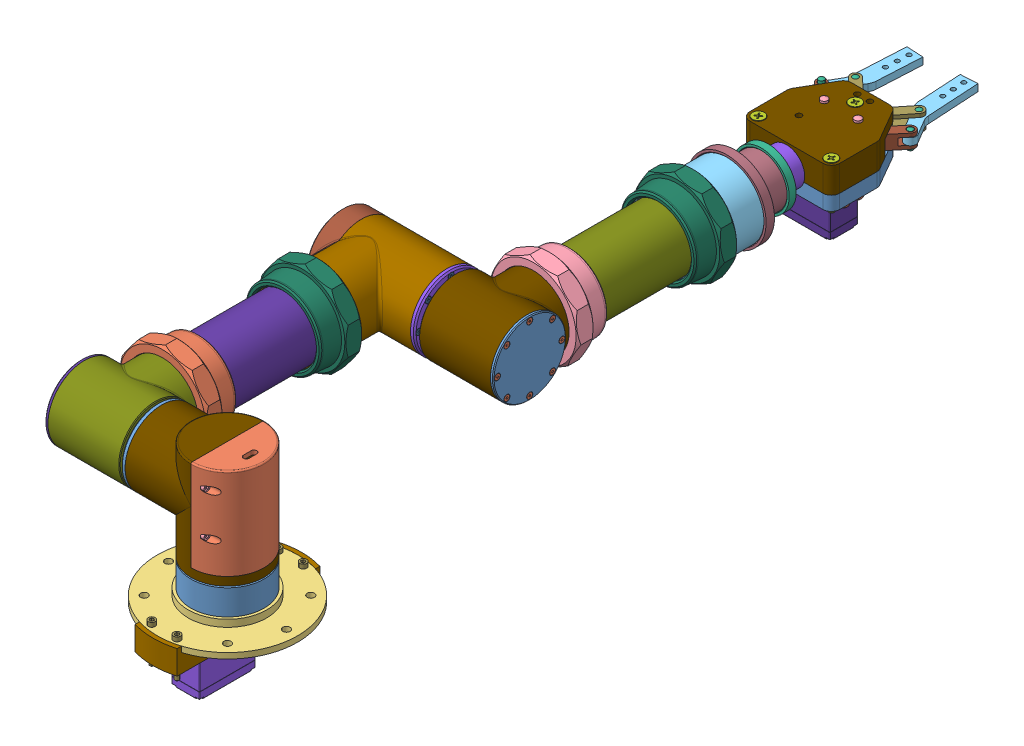
SolidWorks assembly СборкаМанипулятораИСхвата, configuration По умолчанию. Lengths in mm.
Overall size (176.26 169.71 563.94).
209 component instances, 76 part files, 12 mates.
Components (placement in the parent):
- link_0-1: link_0 [По умолчанию] at origin size (100 73 106)
  - shell_0-2: shell_0 [По умолчанию] x (-1 0 0) z (0 -1 0) size (52 52 23)
  - sleave_external_0-1: sleave_external_0 [00] at (0 12 0) x (0 -1 0) z (0.129917 0 0.991525) size (3 42 42)
  - flange_0-1: flange_0 [По умолчанию] at (0 -4 0) size (100 9 100)
  - screw_M3x10(DIN7991)-1: screw_M3x10(DIN7991) [По умолчанию] at (-11.75 -4 20.3516) x (0.992464 0 0.122536) z (0 -1 0) size (6.72 6.72 10)
  - screw_M3x10(DIN7991)-2: screw_M3x10(DIN7991) [По умолчанию] at (11.75 -4 20.3516) x (0.602352 0 -0.798231) z (0 -1 0) size (6.72 6.72 10)
  - screw_M3x10(DIN7991)-3: screw_M3x10(DIN7991) [По умолчанию] at (23.5 -4 0) x (-0.390112 0 -0.920767) z (0 -1 0) size (6.72 6.72 10)
  - screw_M3x10(DIN7991)-4: screw_M3x10(DIN7991) [По умолчанию] at (11.75 -4 -20.3516) x (-0.992464 0 -0.122536) z (0 -1 0) size (6.72 6.72 10)
  - screw_M3x10(DIN7991)-5: screw_M3x10(DIN7991) [По умолчанию] at (-11.75 -4 -20.3516) x (-0.602352 0 0.798231) z (0 -1 0) size (6.72 6.72 10)
  - screw_M3x10(DIN7991)-6: screw_M3x10(DIN7991) [По умолчанию] at (-23.5 -4 0) x (0.390112 0 0.920767) z (0 -1 0) size (6.72 6.72 10)
  - shaft_0-1: shaft_0 [00] at (0 -4 0) x (0 -1 0) z (-0.151353 0 -0.98848) size (31 32 32)
  - servo_flange-1: servo_flange [По умолчанию] at (0 -1.5 0) x (-0.591938 0 0.805983) z (0.805983 0 0.591938) size (20 4.5 20)
  - screw_M3x8(DIN912)-1: screw_M3x8(DIN912) [По умолчанию] at (5.6419 -6 4.1436) x (-0.618765 0 -0.785576) z (0 -1 0) size (4.6 4.6 10)
  - screw_M3x8(DIN912)-2: screw_M3x8(DIN912) [По умолчанию] at (-4.1436 -6 5.6419) x (0.785576 0 -0.618765) z (0 -1 0) size (4.6 4.6 10)
  - screw_M3x8(DIN912)-3: screw_M3x8(DIN912) [По умолчанию] at (-5.6419 -6 -4.1436) x (0.618765 0 0.785576) z (0 -1 0) size (4.6 4.6 10)
  - screw_M3x8(DIN912)-4: screw_M3x8(DIN912) [По умолчанию] at (4.1436 -6 -5.6419) x (-0.785576 0 0.618765) z (0 -1 0) size (4.6 4.6 10)
  - servo_MG995-1: servo_MG995 [По умолчанию] at (0 -46 10) x (0 0 -1) z (0 1 0) size (55.5 20 44.57)
  - servo_lock-1: servo_lock [По умолчанию] at (0 -17 0) size (30 17 106)
  - screw_M4x14(DIN912)-1: screw_M4x14(DIN912) [По умолчанию] at (-5 -23 -14) x (0.91175 0 0.410745) z (0 -1 0) size (7 7 18)
  - ГайкаM4(DIN936)-1: ГайкаM4(DIN936) [По умолчанию] at (-5 -9 -14) size (7 2.2 8.08)
  - screw_M4x14(DIN912)-2: screw_M4x14(DIN912) [По умолчанию] at (5 -23 -14) x (0.91175 0 0.410745) z (0 -1 0) size (7 7 18)
  - screw_M4x14(DIN912)-3: screw_M4x14(DIN912) [По умолчанию] at (-5 -23 34) x (0.91175 0 0.410745) z (0 -1 0) size (7 7 18)
  - screw_M4x14(DIN912)-4: screw_M4x14(DIN912) [По умолчанию] at (5 -23 34) x (0.91175 0 0.410745) z (0 -1 0) size (7 7 18)
  - ГайкаM4(DIN936)-2: ГайкаM4(DIN936) [По умолчанию] at (5 -9 -14) size (7 2.2 8.08)
  - ГайкаM4(DIN936)-3: ГайкаM4(DIN936) [По умолчанию] at (-5 -9 34) size (7 2.2 8.08)
  - ГайкаM4(DIN936)-4: ГайкаM4(DIN936) [По умолчанию] at (5 -9 34) size (7 2.2 8.08)
  - screw_M3x25(DIN912)-1: screw_M3x25(DIN912) [По умолчанию] at (-9 3 45) x (0.945557 0 -0.325458) z (0 1 0) size (5 5 28)
  - screw_M3x25(DIN912)-2: screw_M3x25(DIN912) [По умолчанию] at (9 3 45) x (0.945557 0 -0.325458) z (0 1 0) size (5 5 28)
  - screw_M3x25(DIN912)-3: screw_M3x25(DIN912) [По умолчанию] at (-9 3 -45) x (0.945557 0 -0.325458) z (0 1 0) size (5 5 28)
  - screw_M3x25(DIN912)-4: screw_M3x25(DIN912) [По умолчанию] at (9 3 -45) x (0.945557 0 -0.325458) z (0 1 0) size (5 5 28)
  - bearing_6905-2RS_0-1: bearing_6905-2RS_0 [00] at (0 21 0) x (0 -1 0) z (-0.716466 0 0.697622) size (9 42 42)
  - sleave_internal_0-1: sleave_internal_0 [00] at (0 12 0) x (0 -1 0) z (0.154614 0 0.987975) size (3 29 29)
  - bearing_6905-2RS_0-2: bearing_6905-2RS_0 [00] at (0 9 0) x (0 -1 0) z (-0.456957 0 0.889489) size (9 42 42)
  - circlip for shafts normal_din-1: circlip for shafts normal_din [Circlip DIN 471 - 25 x 1.2] x (0.876628 0 0.481168) z (0 1 0) size (28.33 31.3 1.2)
- link_2-1: link_2 [00] at (-56 68 0) x (0 0 -1) z (-1 0 0) size (248.92 79.84 95.06)
  - link_2_part_1-1: link_2_part_1 [00] at origin size (82.24 79.84 84.11)
    - case_2_part_1-1: case_2_part_1 [По умолчанию] at origin size (79.09 52.19 55.06)
    - case_cover_2_part_1-1: case_cover_2_part_1 [По умолчанию] at (0 0 46) size (52 52 2)
    - screw_M2x8(DIN7991)_2_part_1-1: screw_M2x8(DIN7991)_2_part_1 [Default] at (-23 0 46.8) x (0 0 -1) z (1 0 0) size (8 4 4)
    - screw_M2x8(DIN7991)_2_part_1-2: screw_M2x8(DIN7991)_2_part_1 [Default] at (-16.2635 16.2635 46.8) x (0 0 -1) z (1 0 0) size (8 4 4)
    - screw_M2x8(DIN7991)_2_part_1-3: screw_M2x8(DIN7991)_2_part_1 [Default] at (0 23 46.8) x (0 0 -1) z (1 0 0) size (8 4 4)
    - screw_M2x8(DIN7991)_2_part_1-4: screw_M2x8(DIN7991)_2_part_1 [Default] at (16.2635 16.2635 46.8) x (0 0 -1) z (1 0 0) size (8 4 4)
    - screw_M2x8(DIN7991)_2_part_1-5: screw_M2x8(DIN7991)_2_part_1 [Default] at (23 0 46.8) x (0 0 -1) z (1 0 0) size (8 4 4)
    - screw_M2x8(DIN7991)_2_part_1-6: screw_M2x8(DIN7991)_2_part_1 [Default] at (16.2635 -16.2635 46.8) x (0 0 -1) z (1 0 0) size (8 4 4)
    - screw_M2x8(DIN7991)_2_part_1-7: screw_M2x8(DIN7991)_2_part_1 [Default] at (0 -23 46.8) x (0 0 -1) z (1 0 0) size (8 4 4)
    - screw_M2x8(DIN7991)_2_part_1-8: screw_M2x8(DIN7991)_2_part_1 [Default] at (-16.2635 -16.2635 46.8) x (0 0 -1) z (1 0 0) size (8 4 4)
    - bolt_M3x8(DIN912)_2_part_1-1: bolt_M3x8(DIN912)_2_part_1 [По умолчанию] at (4.9497 -4.9497 2) size (4.6 4.6 10)
    - bolt_M3x8(DIN912)_2_part_1-3: bolt_M3x8(DIN912)_2_part_1 [По умолчанию] at (-4.9497 -4.9497 2) size (4.6 4.6 10)
    - bolt_M3x8(DIN912)_2_part_1-4: bolt_M3x8(DIN912)_2_part_1 [По умолчанию] at (-4.9497 4.9497 2) size (4.6 4.6 10)
    - bolt_M3x8(DIN912)_2_part_1-5: bolt_M3x8(DIN912)_2_part_1 [По умолчанию] at (4.9497 4.9497 2) size (4.6 4.6 10)
    - collet_nut_2_part_1-4: collet_nut_2_part_1 [По умолчанию] at (42.2 0 20.5) x (0 -0.949647 -0.313322) z (0 -0.313322 0.949647) size (61.55 26.55 68.27)
  - link_2_part_2-2: link_2_part_2 [00] at (186 0 -1.5) x (0 0 1) z (-0.003987 0.999992 0) size (83.78 107.15 73.54)
    - shaft_2-1: shaft_2 [00] x (1 0 0) z (0 0.906251 -0.422741) size (31 32 32)
    - bearing_6905-2RS-1: bearing_6905-2RS [00] at (-25 0 0) size (9 42 42)
    - sleave_internal_2-1: sleave_internal_2 [00] at (-16 0 0) size (3 29 29)
    - sleave_external_2-2: sleave_external_2 [00] at (-16 0 0) size (3 42 42)
    - bearing_6905-2RS-2: bearing_6905-2RS [00] at (-13 0 0) size (9 42 42)
    - servo_flange_2-1: servo_flange_2 [По умолчанию] at (-2.5 0 0) x (0 -0.341893 0.939739) z (0 0.939739 0.341893) size (20 4.5 20)
    - bearing_cover_2-1: bearing_cover_2 [00] at (-28 0 0) x (1 0 0) z (0 0.709921 0.704282) size (3.19 52 52)
    - case_2_part_2-3: case_2_part_2 [00] at (-25 0 0) x (1 0 0) z (0 0.003987 0.999992) size (72.93 93 52.14)
    - servo_MG995-2: servo_MG995 [По умолчанию] at (42 -9.9999 0.0399) x (0 0.999992 -0.003987) z (-1 0 0) size (55.5 20 44.57)
    - screw_M2x10(DIN7991)_2_part_2-2: screw_M2x10(DIN7991)_2_part_2 [Default] at (-26.8 22.9998 -0.0917) x (1 0 0) z (0 -0.003987 -0.999992) size (10 4 4)
    - case_cover_2_part_2-2: case_cover_2_part_2 [00] at (22 0 0) x (0 -0.999992 0.003987) z (0 0.003987 0.999992) size (63 17.67 52)
    - servo_lock_2-1: servo_lock_2 [00] at (8 0 0) x (0 -0.003987 -0.999992) z (1 0 0) size (50 59.91 32.5)
    - bolt_M3x8(DIN912)-1: bolt_M3x8(DIN912) [По умолчанию] at (17 14.0198 4.9441) x (0 -0.003987 -0.999992) z (1 0 0) size (4.6 4.6 10)
    - screw_M2x10(DIN7991)_2_part_2-13: screw_M2x10(DIN7991)_2_part_2 [Default] at (-26.8 16.3282 16.1985) x (1 0 0) z (0 -0.003987 -0.999992) size (10 4 4)
    - screw_M2x10(DIN7991)_2_part_2-14: screw_M2x10(DIN7991)_2_part_2 [Default] at (-26.8 0.0917 22.9998) x (1 0 0) z (0 -0.003987 -0.999992) size (10 4 4)
    - screw_M2x10(DIN7991)_2_part_2-15: screw_M2x10(DIN7991)_2_part_2 [Default] at (-26.8 -16.1985 16.3282) x (1 0 0) z (0 -0.003987 -0.999992) size (10 4 4)
    - screw_M2x10(DIN7991)_2_part_2-16: screw_M2x10(DIN7991)_2_part_2 [Default] at (-26.8 -22.9998 0.0917) x (1 0 0) z (0 -0.003987 -0.999992) size (10 4 4)
    - screw_M2x10(DIN7991)_2_part_2-17: screw_M2x10(DIN7991)_2_part_2 [Default] at (-26.8 -16.3282 -16.1985) x (1 0 0) z (0 -0.003987 -0.999992) size (10 4 4)
    - screw_M2x10(DIN7991)_2_part_2-18: screw_M2x10(DIN7991)_2_part_2 [Default] at (-26.8 -0.0917 -22.9998) x (1 0 0) z (0 -0.003987 -0.999992) size (10 4 4)
    - screw_M2x10(DIN7991)_2_part_2-19: screw_M2x10(DIN7991)_2_part_2 [Default] at (-26.8 16.1985 -16.3282) x (1 0 0) z (0 -0.003987 -0.999992) size (10 4 4)
    - bolt_M3x8(DIN912)-10: bolt_M3x8(DIN912) [По умолчанию] at (2 -2.3933 6.5782) x (0 -0.868012 -0.496543) z (1 0 0) size (4.6 4.6 10)
    - bolt_M3x8(DIN912)-11: bolt_M3x8(DIN912) [По умолчанию] at (2 6.5782 2.3933) x (0 -0.868012 -0.496543) z (1 0 0) size (4.6 4.6 10)
    - bolt_M3x8(DIN912)-12: bolt_M3x8(DIN912) [По умолчанию] at (2 2.3933 -6.5782) x (0 -0.868012 -0.496543) z (1 0 0) size (4.6 4.6 10)
    - bolt_M3x8(DIN912)-13: bolt_M3x8(DIN912) [По умолчанию] at (2 -6.5782 -2.3933) x (0 -0.868012 -0.496543) z (1 0 0) size (4.6 4.6 10)
    - bolt_M3x8(DIN912)-15: bolt_M3x8(DIN912) [По умолчанию] at (17 13.98 -5.0558) x (0 -0.003987 -0.999992) z (1 0 0) size (4.6 4.6 10)
    - bolt_M3x8(DIN912)-16: bolt_M3x8(DIN912) [По умолчанию] at (17 -33.9798 5.1355) x (0 -0.003987 -0.999992) z (1 0 0) size (4.6 4.6 10)
    - bolt_M3x8(DIN912)-17: bolt_M3x8(DIN912) [По умолчанию] at (17 -34.0197 -4.8644) x (0 -0.003987 -0.999992) z (1 0 0) size (4.6 4.6 10)
    - screw_M2x16(DIN7991)_2_part_2-6: screw_M2x16(DIN7991)_2_part_2 [Default] at (48.3 0.0917 22.9998) x (-1 0 0) z (0 -0.003987 -0.999992) size (16 4 4)
    - screw_M2x16(DIN7991)_2_part_2-7: screw_M2x16(DIN7991)_2_part_2 [Default] at (48.3 16.3282 16.1985) x (-1 0 0) z (0 -0.003987 -0.999992) size (16 4 4)
    - screw_M2x16(DIN7991)_2_part_2-8: screw_M2x16(DIN7991)_2_part_2 [Default] at (48.3 22.9998 -0.0917) x (-1 0 0) z (0 -0.003987 -0.999992) size (16 4 4)
    - screw_M2x16(DIN7991)_2_part_2-9: screw_M2x16(DIN7991)_2_part_2 [Default] at (48.3 16.1985 -16.3282) x (-1 0 0) z (0 -0.003987 -0.999992) size (16 4 4)
    - screw_M2x16(DIN7991)_2_part_2-10: screw_M2x16(DIN7991)_2_part_2 [Default] at (48.3 -0.0917 -22.9998) x (-1 0 0) z (0 -0.003987 -0.999992) size (16 4 4)
    - collet_nut_2_part_2-1: collet_nut_2_part_2 [По умолчанию] at (22 -56.1996 0.2241) x (-1 0 0) z (0 0.003987 0.999992) size (61.55 26.55 68.27)
    - circlip for shafts normal_din-1: circlip for shafts normal_din [Circlip DIN 471 - 25 x 1.2] at (-4 0 0) x (0 0.144431 0.989515) z (-1 0 0) size (28.33 31.3 1.2)
    - A_DB9-1: A_DB9 [По умолчанию] at (5.9719 -16.7195 3.89) x (1 0 0) z (0 0.003987 0.999992) size (30.9 12.5 15.5)
  - pipe_2-1: pipe_2 [По умолчанию] at (146 0 20.5) x (-1 0 0) z (0 -0.924225 -0.381849) size (120 45 45)
- link_3-1: link_3 [00] at (-18.5 68 -186) x (0 0 -1) z (1 0 0) size (230.5 111.41 111.41)
  - link_3_part_1-1: link_3_part_1 [00] at origin size (82.24 72.44 77.89)
    - case_3_part_1-2: case_3_part_1 [По умолчанию] at origin size (79.09 52.19 55.06)
    - case_cover_3_part_1-1: case_cover_3_part_1 [По умолчанию] at (0 0 46) size (52 52 2)
    - screw_M2x8(DIN7991)_3_part_1-1: screw_M2x8(DIN7991)_3_part_1 [Default] at (-23 0 46.8) x (0 0 -1) z (1 0 0) size (8 4 4)
    - screw_M2x8(DIN7991)_3_part_1-2: screw_M2x8(DIN7991)_3_part_1 [Default] at (-16.2635 16.2635 46.8) x (0 0 -1) z (1 0 0) size (8 4 4)
    - screw_M2x8(DIN7991)_3_part_1-3: screw_M2x8(DIN7991)_3_part_1 [Default] at (0 23 46.8) x (0 0 -1) z (1 0 0) size (8 4 4)
    - screw_M2x8(DIN7991)_3_part_1-4: screw_M2x8(DIN7991)_3_part_1 [Default] at (16.2635 16.2635 46.8) x (0 0 -1) z (1 0 0) size (8 4 4)
    - screw_M2x8(DIN7991)_3_part_1-5: screw_M2x8(DIN7991)_3_part_1 [Default] at (23 0 46.8) x (0 0 -1) z (1 0 0) size (8 4 4)
    - screw_M2x8(DIN7991)_3_part_1-6: screw_M2x8(DIN7991)_3_part_1 [Default] at (16.2635 -16.2635 46.8) x (0 0 -1) z (1 0 0) size (8 4 4)
    - screw_M2x8(DIN7991)_3_part_1-7: screw_M2x8(DIN7991)_3_part_1 [Default] at (0 -23 46.8) x (0 0 -1) z (1 0 0) size (8 4 4)
    - screw_M2x8(DIN7991)_3_part_1-8: screw_M2x8(DIN7991)_3_part_1 [Default] at (-16.2635 -16.2635 46.8) x (0 0 -1) z (1 0 0) size (8 4 4)
    - bolt_M3x8(DIN912)_3_part_1-1: bolt_M3x8(DIN912)_3_part_1 [По умолчанию] at (4.9497 -4.9497 2) size (4.6 4.6 10)
    - bolt_M3x8(DIN912)_3_part_1-2: bolt_M3x8(DIN912)_3_part_1 [По умолчанию] at (-4.9497 -4.9497 2) size (4.6 4.6 10)
    - bolt_M3x8(DIN912)_3_part_1-3: bolt_M3x8(DIN912)_3_part_1 [По умолчанию] at (-4.9497 4.9497 2) size (4.6 4.6 10)
    - bolt_M3x8(DIN912)_3_part_1-4: bolt_M3x8(DIN912)_3_part_1 [По умолчанию] at (4.9497 4.9497 2) size (4.6 4.6 10)
    - A_DB9-2: A_DB9 [По умолчанию] at (16.7349 -4.8234 11.4719) x (0 0 1) z (0 -1 0) size (30.9 12.5 15.5)
    - collet_nut_3_part_1-2: collet_nut_3_part_1 [По умолчанию] at (42.2 0 20.5) x (0 -0.984916 -0.173035) z (0 -0.173035 0.984916) size (61.55 26.55 68.27)
  - link_3_part_2-1: link_3_part_2 [По умолчанию] at (135 0 20.5) x (0 -0.775896 -0.63086) z (1 0 0) size (79.2 79.2 85.94)
    - case_3_part_2-2: case_3_part_2 [По умолчанию] at origin size (52.23 52.12 48.29)
    - case_cover_3_part_2-1: case_cover_3_part_2 [По умолчанию] at (0 0 59.5) x (-0.707107 -0.707107 0) z (0 0 1) size (40 40 5)
    - servo_MG90S-1: servo_MG90S [Default] at (-5.25 0 12) x (1 0 0) z (0 -1 0) size (32.2 32.5 12.4)
    - servo_flange_3-2: servo_flange_3 [По умолчанию] at (0 0 44.5) x (0.820742 -0.5713 0) z (0 0 -1) size (17 17 8)
    - bearing_6803-1: bearing_6803 [По умолчанию] at (0 0 54.5) x (0.864131 -0.503266 0) z (0 0 1) size (26 26 5)
    - bearing_6803-2: bearing_6803 [По умолчанию] at (0 0 53) x (-0.923728 -0.383049 0) z (0 0 -1) size (26 26 5)
    - shaft_3_part_2-1: shaft_3_part_2 [По умолчанию] at (0 0 44.5) x (-0.820742 0.5713 0) z (0.5713 0.820742 0) size (20 25 20)
    - ext_sleeve_3_part_2-1: ext_sleeve_3_part_2 [По умолчанию] at (0 0 54.5) x (-0.923728 -0.383049 0) z (0 0 -1) size (26 26 1.5)
    - int_sleeve_3_part_2-1: int_sleeve_3_part_2 [По умолчанию] at (0 0 54.5) x (-0.923728 -0.383049 0) z (0 0 -1) size (19 19 1.5)
    - nozzle_3_part_2-1: nozzle_3_part_2 [По умолчанию] at (0 0 35) x (0.707107 0.707107 0) z (0.707107 -0.707107 0) size (56 26.5 56)
    - screw_M2_3_part_2-1: screw_M2_3_part_2 [По умолчанию] at (-15.5563 -15.5563 38.6206) x (0 0 -1) z (-0.898959 0.438032 0) size (8 3.8 3.77)
    - screw_M2_3_part_2-2: screw_M2_3_part_2 [По умолчанию] at (-15.5563 15.5563 38.6206) x (0 0 -1) z (0.438032 0.898959 0) size (8 3.8 3.77)
    - screw_M2_3_part_2-3: screw_M2_3_part_2 [По умолчанию] at (15.5563 15.5563 38.6206) x (0 0 -1) z (0.898959 -0.438032 0) size (8 3.8 3.77)
    - screw_M2_3_part_2-4: screw_M2_3_part_2 [По умолчанию] at (15.5563 -15.5563 38.6206) x (0 0 -1) z (-0.438032 -0.898959 0) size (8 3.8 3.77)
    - screw_M2_3_part_2-5: screw_M2_3_part_2 [По умолчанию] at (10.9602 10.9602 62.1206) x (0 0 -1) z (0.997978 0.063567 0) size (8 3.8 3.77)
    - screw_M2_3_part_2-6: screw_M2_3_part_2 [По умолчанию] at (10.9602 -10.9602 62.1206) x (0 0 -1) z (0.063567 -0.997978 0) size (8 3.8 3.77)
    - screw_M2_3_part_2-7: screw_M2_3_part_2 [По умолчанию] at (-10.9602 -10.9602 62.1206) x (0 0 -1) z (-0.997978 -0.063567 0) size (8 3.8 3.77)
    - screw_M2_3_part_2-8: screw_M2_3_part_2 [По умолчанию] at (-10.9602 10.9602 62.1206) x (0 0 -1) z (-0.063567 0.997978 0) size (8 3.8 3.77)
    - collet_nut_3_part_2-2: collet_nut_3_part_2 [По умолчанию] at (0 0 -2.4) x (0.178047 0.984022 0) z (-0.984022 0.178047 0) size (61.55 26.55 68.27)
  - pipe_3-1: pipe_3 [По умолчанию] at (26 0 20.5) x (1 0 0) z (0 -0.068443 0.997655) size (120 45 45)
- Сборка схват-1: Сборка схват [По умолчанию] at (2.0001 25 -417.5) x (-1 0 0) z (0 1 0) size (84.23 127.44 59.75)
  - MG995-1: MG995 [По умолчанию] at origin size (55.5 20 44.57)
  - Корпус 2-1: Корпус 2 [По умолчанию] at (-31.9999 21 57.5) x (1 0 0) z (0 0 -1) size (64 60 18.5)
  - 1-1: 1 [По умолчанию] at (32 21 29) x (-1 0 0) z (0 0 1) size (64 60 10)
  - DIN912-M4x12-1: DIN912-M4x12 [По умолчанию] at (-24 -5 23) x (0 0 1) z (-0.460546 -0.887636 0) size (16.28 7 7)
  - DIN912-M4x12-2: DIN912-M4x12 [По умолчанию] at (24 5 23) x (0 0 1) z (-0.748354 -0.663299 0) size (16.28 7 7)
  - DIN912-M4x12-3: DIN912-M4x12 [По умолчанию] at (-24 5 23) x (0 0 1) z (-0.997931 0.0643 0) size (16.28 7 7)
  - DIN912-M4x12-4: DIN912-M4x12 [По умолчанию] at (24 -5 23) x (0 0 1) z (0.475534 0.879697 0) size (16.28 7 7)
  - DIN934-M4-2: DIN934-M4 [По умолчанию] at (-24 5 34.5) size (7.43 8.21 3.68)
  - DIN934-M4-3: DIN934-M4 [По умолчанию] at (24 5 34.5) size (7.43 8.21 3.68)
  - DIN934-M4-4: DIN934-M4 [По умолчанию] at (24 -5 34.5) size (7.43 8.21 3.68)
  - DIN934-M4-5: DIN934-M4 [По умолчанию] at (-24 -5 34.5) size (7.43 8.21 3.68)
  - DIN7 D5-L30-1: DIN7 D5-L30 [По умолчанию] at (12.0501 -18 59) x (0 0 -1) z (-0.738585 -0.67416 0) size (31.5 5 5)
  - DIN7 D5-L30-2: DIN7 D5-L30 [По умолчанию] at (-12.05 -18 29) x (0 0 1) z (-0.114483 -0.993425 0) size (31.5 5 5)
  - 6_GRIPPER_ARM-1: 6_GRIPPER_ARM [По умолчанию] at (19.5271 -90.1357 48) x (0.998564 -0.053577 0) z (0.053577 0.998564 0) size (19.3 5 59)
  - 6_GRIPPER_ARM-2: 6_GRIPPER_ARM [По умолчанию] at (-16.594 -92.6626 43) x (-0.998298 -0.058319 0) z (-0.058319 0.998298 0) size (19.3 5 59)
  - DIN7 D4-L12-1: DIN7 D4-L12 [По умолчанию] at (31.7605 -35.713 40.5) x (0 0 1) z (-0.956281 -0.292448 0) size (13.2 4 4)
  - DIN7 D4-L12-2: DIN7 D4-L12 [По умолчанию] at (-29.0857 -38.2986 50.5) x (0 0 -1) z (0.459318 0.888272 0) size (13.2 4 4)
  - DIN7046-1_M4x30-1: DIN7046-1_M4x30 [По умолчанию] at (26.0001 15 57.85) x (0 0 -1) z (0.831237 0.555919 0) size (33.09 8.4 8.4)
  - DIN7046-1_M4x30-2: DIN7046-1_M4x30 [По умолчанию] at (0 -28 57.85) x (0 0 -1) z (0.888568 -0.458744 0) size (33.09 8.4 8.4)
  - DIN7046-1_M4x30-3: DIN7046-1_M4x30 [По умолчанию] at (-26 15 57.85) x (0 0 -1) z (0.988915 -0.148483 0) size (33.09 8.4 8.4)
  - DIN934-M4-6: DIN934-M4 [По умолчанию] at (-26 15 29) size (7.43 8.21 3.68)
  - DIN934-M4-7: DIN934-M4 [По умолчанию] at (26 15 32.2) x (0.467399 -0.884046 0) z (0 0 -1) size (7.43 8.21 3.68)
  - DIN934-M4-8: DIN934-M4 [По умолчанию] at (0 -28 29) size (7.43 8.21 3.68)
  - ФланецСхват-1: ФланецСхват [По умолчанию] at (0.0001 34 43) x (0 -1 0) z (1 0 0) size (13 26 26)
  - втулка-2: втулка [По умолчанию] at (-12.05 -18 39) size (10 10 1.5)
  - втулка-3: втулка [По умолчанию] at (12.0501 -18 39) x (0.833208 0.552959 0) z (0 0 1) size (10 10 1.5)
  - втулка-4: втулка [По умолчанию] at (12.0501 -18 50.5) size (10 10 1.5)
  - втулка-6: втулка [По умолчанию] at (-11.3 -18 50.5) x (0.832508 0.554013 0) z (0 0 1) size (10 10 1.5)
  - ВалШестерня-3: ВалШестерня [Вал-шестерня] at (10 0 44.5) x (0 0 1) z (-0.995943 -0.08999 0) size (10 13.61 13.61)
  - КолесоКривошип-1: КолесоКривошип [Колесо-кривошип] at (12.0501 -18 44.5) x (0 0 1) z (0.668414 0.74379 0) size (10 42.92 25.84)
  - КолесоКривошип-2: КолесоКривошип [Колесо-кривошип] at (-12.05 -18 44.5) x (0 0 1) z (0.765986 -0.642858 0) size (10 42.92 25.84)
  - Кривошип-1: Кривошип [По умолчанию] at (-22.8002 -51.3883 39) x (0 0 1) z (-0.782673 0.622433 0) size (11.5 32 7)
  - DIN7 D4-L12-3: DIN7 D4-L12 [По умолчанию] at (-4.5 -34 38.5) x (0 0 1) z (-0.987062 -0.160337 0) size (13.2 4 4)
  - DIN7 D4-L12-4: DIN7 D4-L12 [По умолчанию] at (22.8082 -51.0239 38.5) x (0 0 1) z (0.96775 -0.251914 0) size (13.2 4 4)
  - DIN7 D4-L12-5: DIN7 D4-L12 [По умолчанию] at (4.5001 -34 50.5) x (0 0 -1) z (0.977007 -0.213205 0) size (13.2 4 4)
  - DIN7 D4-L12-6: DIN7 D4-L12 [По умолчанию] at (-20.0608 -53.5668 50.5) x (0 0 -1) z (0.991151 0.13274 0) size (13.2 4 4)
  - Кривошип-2: Кривошип [По умолчанию] at (20.4248 -53.587 39) x (0 0 1) z (-0.680955 -0.732326 0) size (11.5 32 7)
  - gayka_m2-1: gayka_m2 [По умолчанию] at (0 13.4 37) x (0.888267 0 -0.459328) z (0 1 0) size (4.25 4.76 2.06)
  - gayka_m2-2: gayka_m2 [По умолчанию] at (0.0001 13.4 49) x (0.888267 0 -0.459328) z (0 1 0) size (4.25 4.76 2.06)
  - gayka_m2-3: gayka_m2 [По умолчанию] at (-5.9999 13.4 43) x (0.888267 0 -0.459328) z (0 1 0) size (4.25 4.76 2.06)
  - gayka_m2-5: gayka_m2 [По умолчанию] at (6.0001 13.4 43) x (0.888267 0 -0.459328) z (0 1 0) size (4.25 4.76 2.06)
  - DIN912-M2x12-1: DIN912-M2x12 [По умолчанию] at (6.0001 26 43) x (0 -1 0) z (0.6502 0 0.759763) size (14.19 3.8 3.8)
  - DIN912-M2x12-2: DIN912-M2x12 [По умолчанию] at (0.0001 26 37) x (0 -1 0) z (0.733895 0 0.679263) size (14.19 3.8 3.8)
  - DIN912-M2x12-3: DIN912-M2x12 [По умолчанию] at (-5.9999 26 43) x (0 -1 0) z (0.223689 0 0.97466) size (14.19 3.8 3.8)
  - DIN912-M2x12-4: DIN912-M2x12 [По умолчанию] at (0.0001 26 49) x (0 -1 0) z (0.998157 0 0.060686) size (14.19 3.8 3.8)
- link_1-1: link_1 [00] at (75.0032 62.3733 78.1793) x (-0.958621 0.020437 -0.283952) z (0 -0.99742 -0.071787) size (90.29 75.39 79.42)
  - shaft_1-1: shaft_1 [00] at (115.3034 47.5227 0) x (-0.958621 0.284686 0) z (-0.241828 -0.814306 -0.52766) size (31 32 32)
  - servo_flange-1: servo_flange [По умолчанию] at (117.7 46.8109 0) x (-0.277218 -0.933474 0.227544) z (-0.064779 -0.218128 -0.973768) size (20 4.5 20)
  - bearing_6905-2RS-1: bearing_6905-2RS [00] at (139.2689 40.4055 0) x (-0.958621 0.284686 0) z (0 0 1) size (9 42 42)
  - bearing_6905-2RS-2: bearing_6905-2RS [00] at (127.7655 43.8217 0) x (-0.958621 0.284686 0) z (0 0 1) size (9 42 42)
  - sleave_external_1-1: sleave_external_1 [00] at (130.6414 42.9677 0) x (-0.958621 0.284686 0) z (0 0 1) size (3 42 42)
  - sleave_internal_1-1: sleave_internal_1 [00] at (130.6414 42.9677 0) x (-0.958621 0.284686 0) z (0 0 1) size (3 29 29)
  - case_1-1: case_1 [По умолчанию] at (93.3146 50.7578 43.8865) x (0.283952 0.956148 0.071787) z (-0.958621 0.284686 0) size (52 71 73)
  - servo_MG995-1: servo_MG995 [По умолчанию] at (74.3577 58.9337 9.9742) x (0.020437 0.068816 -0.99742) z (0.958621 -0.284686 0) size (55.5 20 44.57)
  - bearing_cover_1-1: bearing_cover_1 [00] at (142.1448 39.5515 0) x (-0.958621 0.284686 0) z (-0.020437 -0.068816 0.99742) size (3.19 52 52)
  - case_cover_1-2: case_cover_1 [По умолчанию] at (93.4372 51.1707 37.902) x (0.283952 0.956148 0.071787) z (-0.958621 0.284686 0) size (52 65 27.19)
  - slotted countersunk flat head screw_iso-39: slotted countersunk flat head screw_iso [ISO 2009 - M2 x 8 - 8N] at (135.6139 17.5601 -1.6511) x (-0.958621 0.284686 0) z (0.021773 0.073316 0.997071) size (8 3.8 3.77)
  - slotted countersunk flat head screw_iso-40: slotted countersunk flat head screw_iso [ISO 2009 - M2 x 8 - 8N] at (137.1944 22.882 15.054) x (-0.958621 0.284686 0) z (0.21611 0.727704 0.650956) size (8 3.8 3.77)
  - slotted countersunk flat head screw_iso-41: slotted countersunk flat head screw_iso [ISO 2009 - M2 x 8 - 8N] at (141.6748 37.9687 22.9407) x (-0.958621 0.284686 0) z (0.283852 0.955813 -0.076481) size (8 3.8 3.77)
  - slotted countersunk flat head screw_iso-42: slotted countersunk flat head screw_iso [ISO 2009 - M2 x 8 - 8N] at (146.4305 53.9825 17.389) x (-0.958621 0.284686 0) z (0.185318 0.62402 -0.759116) size (8 3.8 3.77)
  - slotted countersunk flat head screw_iso-43: slotted countersunk flat head screw_iso [ISO 2009 - M2 x 8 - 8N] at (148.6757 61.5428 1.6511) x (-0.958621 0.284686 0) z (-0.021773 -0.073316 -0.997071) size (8 3.8 3.77)
  - slotted countersunk flat head screw_iso-44: slotted countersunk flat head screw_iso [ISO 2009 - M2 x 8 - 8N] at (147.0952 56.2209 -15.054) x (-0.958621 0.284686 0) z (-0.21611 -0.727704 -0.650956) size (8 3.8 3.77)
  - slotted countersunk flat head screw_iso-45: slotted countersunk flat head screw_iso [ISO 2009 - M2 x 8 - 8N] at (142.6149 41.1342 -22.9407) x (-0.958621 0.284686 0) z (-0.283852 -0.955813 0.076481) size (8 3.8 3.77)
  - slotted countersunk flat head screw_iso-46: slotted countersunk flat head screw_iso [ISO 2009 - M2 x 8 - 8N] at (137.8591 25.1204 -17.389) x (-0.958621 0.284686 0) z (-0.185318 -0.62402 0.759116) size (8 3.8 3.77)
  - socket head cap screw_iso-25: socket head cap screw_iso [ISO 4762 M2.5 x 10 - 10N] at (79.8207 35.1776 -15.615) x (0.958621 -0.284686 0) z (0.249729 0.84091 -0.48011) size (12.5 4.5 4.5)
  - socket head cap screw_iso-29: socket head cap screw_iso [ISO 4762 M2.5 x 10 - 10N] at (79.2076 33.1131 14.3076) x (0.958621 -0.284686 0) z (0.249729 0.84091 -0.48011) size (12.5 4.5 4.5)
  - socket head cap screw_iso-27: socket head cap screw_iso [ISO 4762 M2.5 x 10 - 10N] at (92.8825 79.1604 -12.3128) x (0.958621 -0.284686 0) z (0.249729 0.84091 -0.48011) size (12.5 4.5 4.5)
  - socket head cap screw_iso-28: socket head cap screw_iso [ISO 4762 M2.5 x 10 - 10N] at (92.2694 77.0959 17.6098) x (0.958621 -0.284686 0) z (0.249729 0.84091 -0.48011) size (12.5 4.5 4.5)
  - socket head cap screw_iso-20: socket head cap screw_iso [ISO 4762 M3 x 8 - 8N] at (96.4353 48.972 -14.3228) x (0.958621 -0.284686 0) z (-0.07713 -0.259718 0.962599) size (11 5.5 5.5)
  - socket head cap screw_iso-24: socket head cap screw_iso [ISO 4762 M3 x 8 - 8N] at (95.4543 45.6689 33.5533) x (0.958621 -0.284686 0) z (-0.07713 -0.259718 0.962599) size (11 5.5 5.5)
  - socket head cap screw_iso-22: socket head cap screw_iso [ISO 4762 M3 x 8 - 8N] at (99.2748 58.5335 -13.6049) x (0.958621 -0.284686 0) z (-0.07713 -0.259718 0.962599) size (11 5.5 5.5)
  - socket head cap screw_iso-23: socket head cap screw_iso [ISO 4762 M3 x 8 - 8N] at (98.2939 55.2303 34.2712) x (0.958621 -0.284686 0) z (-0.07713 -0.259718 0.962599) size (11 5.5 5.5)
  - socket head cap screw_iso-4: socket head cap screw_iso [ISO 4762 M3 x 8 - 8N] at (112.881 49.9036 6.8164) x (0.958621 -0.284686 0) z (-0.083742 -0.281985 -0.955757) size (11 5.5 5.5)
  - socket head cap screw_iso-5: socket head cap screw_iso [ISO 4762 M3 x 8 - 8N] at (114.3681 54.911 -1.5928) x (0.958621 -0.284686 0) z (-0.272091 -0.916209 0.294157) size (11 5.5 5.5)
  - socket head cap screw_iso-6: socket head cap screw_iso [ISO 4762 M3 x 8 - 8N] at (111.9741 46.8498 -6.8164) x (0.958621 -0.284686 0) z (0.083742 0.281985 0.955757) size (11 5.5 5.5)
  - socket head cap screw_iso-7: socket head cap screw_iso [ISO 4762 M3 x 8 - 8N] at (110.487 41.8424 1.5928) x (0.958621 -0.284686 0) z (0.272091 0.916209 -0.294157) size (11 5.5 5.5)
  - slotted countersunk flat head screw_iso-47: slotted countersunk flat head screw_iso [ISO 2009 - M3 x 12 - 12N] at (91.4495 44.4777 37.3995) x (-0.020437 -0.068816 0.99742) z (0.9994 0.0265 0.022306) size (12 5.5 5.44)
  - slotted countersunk flat head screw_iso-48: slotted countersunk flat head screw_iso [ISO 2009 - M3 x 12 - 12N] at (86.7268 53.1635 37.902) x (-0.020437 -0.068816 0.99742) z (0.027967 -0.997277 -0.068233) size (12 5.5 5.44)
  - slotted countersunk flat head screw_iso-49: slotted countersunk flat head screw_iso [ISO 2009 - M3 x 12 - 12N] at (95.4248 57.8638 38.4045) x (-0.020437 -0.068816 0.99742) z (-0.9994 -0.0265 -0.022306) size (12 5.5 5.44)
  - slotted countersunk flat head screw_iso-50: slotted countersunk flat head screw_iso [ISO 2009 - M3 x 12 - 12N] at (100.1475 49.1779 37.902) x (-0.020437 -0.068816 0.99742) z (-0.027967 0.997277 0.068233) size (12 5.5 5.44)
  - circlip for shafts normal_din-1: circlip for shafts normal_din [Circlip DIN 471 - 25 x 1.2] at (119.1379 46.3839 0) x (0 0 -1) z (0.958621 -0.284686 0) size (28.33 31.3 1.2)
Mates (geometry in assembly coordinates):
- Концентричный4: concentric anti-aligned: cylinder of link_2-1/link_2_part_2-2/case_2_part_2-3 through (-29.5 68 -186) axis (1 0 0) radius 26; cylinder of link_3-1/link_3_part_1-1/case_3_part_1-2 through (27.5 68 -186) axis (-1 0 0) radius 26
- Совпадение4: coincident anti-aligned: plane of link_3-1/link_3_part_2-1/case_cover_3_part_2-1 through (2 68 -383.5) normal (0 0 -1); plane of Сборка схват-1/ФланецСхват-1 through (2 58 -383.5) normal (0 0 1)
- Концентричный5: concentric aligned: cylinder of link_3-1/link_3_part_2-1/shaft_3_part_2-1 through (2 68 -390.5) axis (0 0 1) radius 10; cylinder of Сборка схват-1/ФланецСхват-1 through (2 68 -383.5) axis (0 0 1) radius 10
- Угол3: planar angle anti-aligned: plane of link_2-1/link_2_part_1-1/case_2_part_1-1 through (-56 68 0) normal (0 -1 0); plane of link_3-1/link_3_part_1-1/case_3_part_1-2 through (-18.5 68 -186) normal (0 1 0)
- Угол4: planar angle aligned: plane of link_3-1/link_3_part_1-1/case_3_part_1-2 through (-18.5 68 -186) normal (0 1 0); plane of Сборка схват-1/MG995-1 through (2.0001 25 -417.5) normal (0 1 0)
- Совпадение9: coincident anti-aligned: plane of link_2-1/link_2_part_2-2/shaft_2-1 through (-23.5 82.5269 -179.294) normal (1 0 0); plane of link_3-1/link_3_part_1-1/case_3_part_1-2 through (-23.5 68 -186) normal (-1 0 0)
- Концентричный7: concentric anti-aligned: cylinder of link_0-1/shell_0-2 through (0 0 0) axis (0 -1 0) radius 26; cylinder of link_1-1/case_1-1 through (0 97.6815 0) axis (0 1 0) radius 26
- Концентричный8: concentric aligned: cylinder of link_2-1/link_2_part_1-1/case_2_part_1-1 through (-102 68 0) axis (1 0 0) radius 26; cylinder of link_1-1/case_1-1 through (-47 68 0) axis (1 0 0) radius 26
- Совпадение10: coincident anti-aligned: plane of link_0-1/shaft_0-1 through (-15.8157 27 2.4216) normal (0 1 0); plane of link_1-1/case_1-1 through (0 27 0) normal (0 -1 0)
- Совпадение11: coincident anti-aligned: plane of link_2-1/link_2_part_1-1/case_2_part_1-1 through (-53 68 0) normal (1 0 0); plane of link_1-1/shaft_1-1 through (-53 82.1623 -7.4451) normal (-1 0 0)
- Угол1: planar angle aligned: line of link_0-1/servo_lock-1 through (15 -17 50.8331) axis (0 0 -1); axis of link_1-1/case_1-1 through (-18.2491 68 0) axis (1 0 0)
- Угол2: planar angle aligned: axis of link_2-1/pipe_2-1 through (-76.5 68 -26) axis (0 0 -1); axis of link_1-1/case_cover_1-2 through (0 94 0) axis (0 -1 0)
